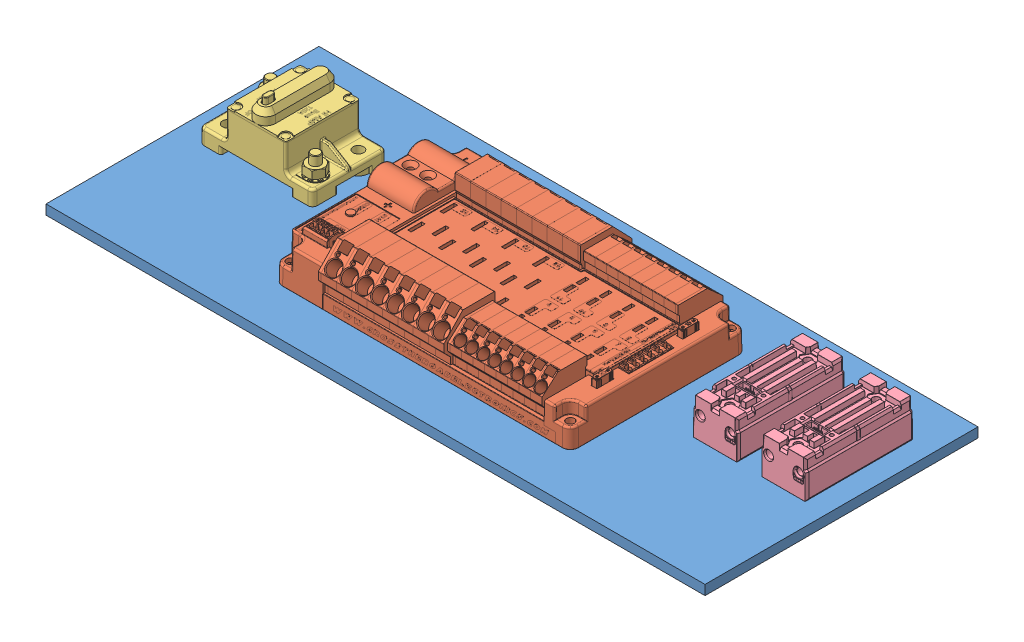
SolidWorks assembly top board, configuration Default. Lengths in mm.
Overall size (429.26 48.5 177.8).
5 component instances, 4 part files, 12 mates.
Components (placement in the parent):
- board 2-1: board 2 [Default] at (-361.6521 10.7419 157.0266) size (429.26 6.35 177.8)
- PDP-1: PDP [Default] at (-142.6393 23.7721 69.1088) size (192.68 36.15 120.93)
- Breaker-1: Breaker [Default] at (-309.1683 21.9179 48.6004) size (73.72 42.2 48.95)
- Speed Controller-1: Speed Controller [Default] at (-5.0221 32.9294 42.806) x (1 0 0) z (0 -1 0) size (30.12 70.11 24.39)
- Speed Controller-2: Speed Controller [Default] at (39.4279 32.9294 42.806) x (1 0 0) z (0 -1 0) size (30.12 70.11 24.39)
Mates (geometry in assembly coordinates):
- Coincident1: coincident anti-aligned: plane of board 2-1 through (-361.6521 17.0919 157.0266) normal (0 1 0); plane of PDP-1 through (-50.6151 17.0919 126.5128) normal (0 -1 0)
- Distance1: distance = 127 mm aligned: plane of PDP-1 through (-234.6521 47.6337 106.9566) normal (-1 0 0); plane of board 2-1 through (-361.6521 17.0919 157.0266) normal (-1 0 0)
- Coincident4: coincident: plane of board 2-1 through (-361.6521 17.0919 157.0266) normal (0 1 0); plane of Breaker-1 through (-277.6813 17.0919 71.2996) normal (0 -1 0)
- Coincident5: coincident: plane of board 2-1 through (-361.6521 17.0919 157.0266) normal (0 1 0); plane of Speed Controller-1 through (10.0402 17.0919 7.881) normal (0 -1 0)
- Coincident6: coincident: plane of board 2-1 through (-361.6521 17.0919 157.0266) normal (0 1 0); plane of Speed Controller-2 through (54.4902 17.0919 7.881) normal (0 -1 0)
- Distance2: distance = 46.99 mm aligned: plane of PDP-1 through (-227.6521 47.6337 110.0366) normal (0 0 1); plane of board 2-1 through (-361.6521 17.0919 157.0266) normal (0 0 1)
- Distance3: distance = 101.6 mm: plane of Speed Controller-2 through (38.3979 39.5794 55.4266) normal (0 0 1); plane of board 2-1 through (-361.6521 17.0919 157.0266) normal (0 0 1)
- Distance4: distance = 101.6 mm: plane of Speed Controller-1 through (-6.0521 39.5794 55.4266) normal (0 0 1); plane of board 2-1 through (-361.6521 17.0919 157.0266) normal (0 0 1)
- Distance6: distance = 25.4 mm aligned: plane of board 2-1 through (67.6079 17.0919 157.0266) normal (1 0 0); plane of Speed Controller-2 through (42.2079 39.5794 55.0266) normal (1 0 0)
- Distance7: distance = 69.85 mm: plane of Speed Controller-1 through (-2.2421 39.5794 55.0266) normal (1 0 0); line of board 2-1 through (67.6079 17.0919 157.0266) axis (0 0 -1)
- Distance8: distance = 50.8 mm: plane of Breaker-1 through (-310.8521 52.8909 66.3804) normal (-1 0 0); plane of board 2-1 through (-361.6521 17.0919 157.0266) normal (-1 0 0)
- Distance9: distance = 88.9 mm anti-aligned: plane of Breaker-1 through (-283.8012 33.6527 68.1266) normal (0 0 -1); plane of board 2-1 through (-361.6521 17.0919 157.0266) normal (0 0 1)
